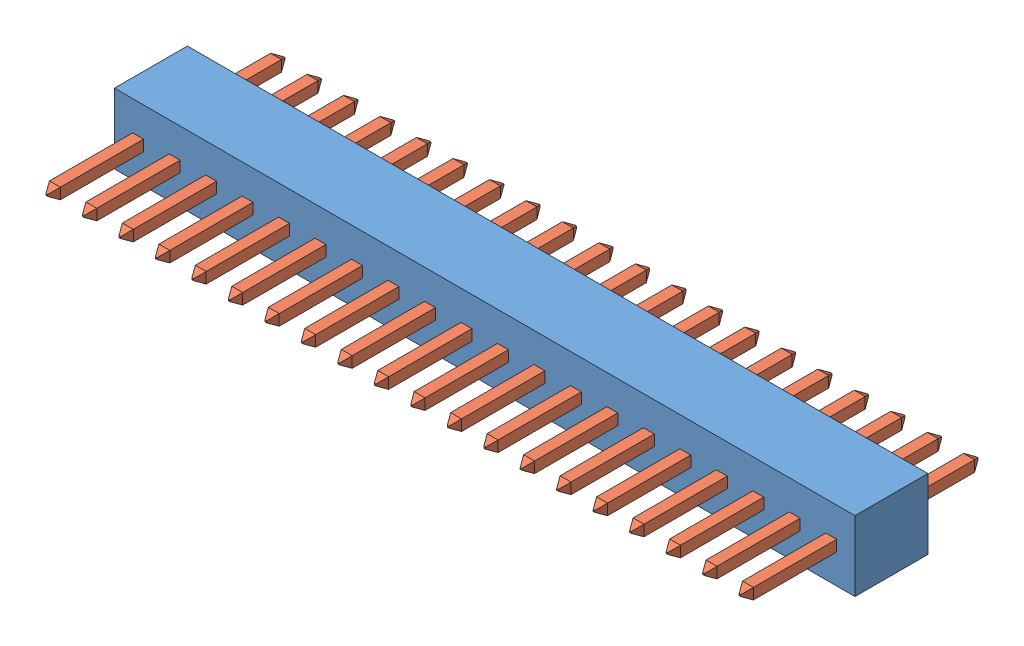
SolidWorks assembly TE_6-104178-1, configuration Default. Lengths in mm.
Overall size (25.78 2.44 8.26).
2 component instances, 2 part files, 6 mates.
Components (placement in the parent):
- 6-104178-1-housing-1: 6-104178-1-housing [Default] at (0 1.22 0) x (1 0 0) z (0 0 -1) size (25.78 2.44 2.54)
- 6-104178-1-pins-1: 6-104178-1-pins [Default] at (0 0 -1.27) x (1 0 0) z (0 -1 0) size (24.51 8.26 0.38)
Mates (geometry in assembly coordinates):
- Coincident1: coincident aligned: plane of 6-104178-1-housing-1 through (0 1.22 0) normal (1 0 0)
- Coincident2: coincident: line of 6-104178-1-housing-1 through (-12.89 0 -1.27) axis (1 0 0)
- Coincident4: coincident anti-aligned: plane of 6-104178-1-housing-1 through (0 1.22 0) normal (0 0 -1)
- Coincident5: coincident anti-aligned: plane of 6-104178-1-housing-1 through (-12.89 -1.22 -1.27) normal (0 0 -1); plane of 6-104178-1-pins-1 through (0 0 -1.27) normal (0 0 1)
- Coincident6: coincident aligned: plane of 6-104178-1-housing-1 through (0 1.22 0) normal (1 0 0); plane of 6-104178-1-pins-1 through (0 0 -1.27) normal (1 0 0)
- Coincident7: coincident anti-aligned: plane of 6-104178-1-housing-1 through (-12.255 -0.19 1.271) normal (0 1 0); plane of 6-104178-1-pins-1 through (-12.255 -0.19 -3.81) normal (0 -1 0)
